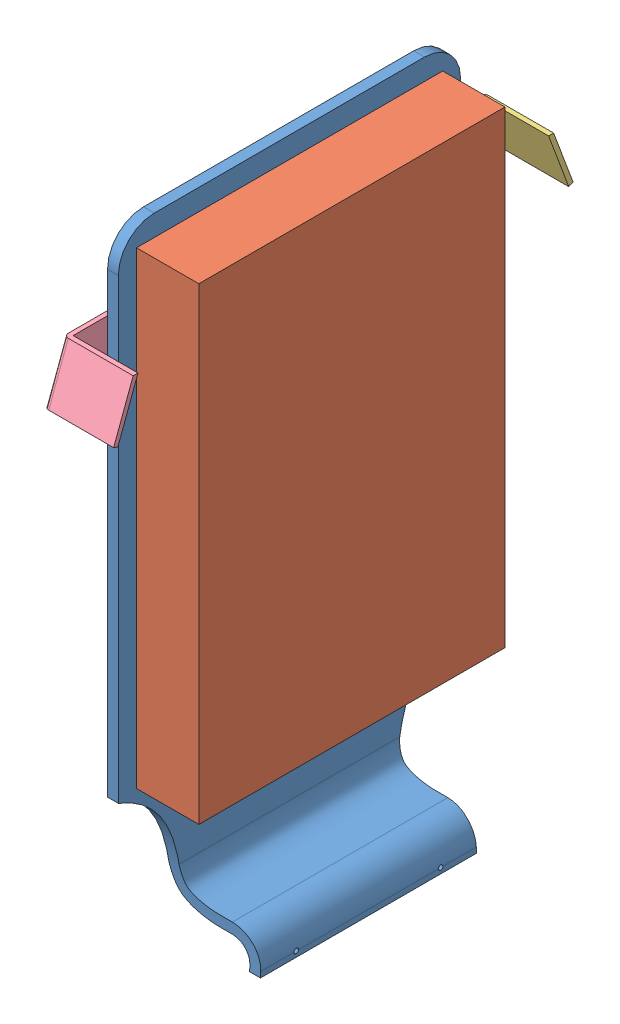
SolidWorks assembly MS-70001-XA-Head Restraint Assembly, configuration Default. Lengths in mm.
Overall size (66.68 448.8 324.07).
4 component instances, 4 part files, 1 mates.
Components (placement in the parent):
- MS-70001-AG-Head_Restraint-1: MS-70001-AG-Head_Restraint [Default] at (207.0378 -6.087 347.9488) size (66.44 448.8 241.3)
- MS-70001-AB-Head Restraint Padding-1: MS-70001-AB-Head Restraint Padding [Default] at (158.9013 216.3377 354.6269) size (43.94 330.2 215.9)
- MS-70001-AC-Right Head Restraint Tab-2: MS-70001-AC-Right Head Restraint Tab [Default] at (147.9793 388.883 235.0151) x (0 0 1) z (-1 0 0) size (49.06 38.1 49.02)
- MS-70001-AC-Left Head Restraint Tab-3: MS-70001-AC-Left Head Restraint Tab [Default] at (151.2813 388.883 461.0827) x (0 0 -1) z (1 0 0) size (48.94 38.1 48.89)
Mates (geometry in assembly coordinates):
- Coincident5: coincident anti-aligned: plane of MS-70001-AG-Head_Restraint-1 through (158.9013 36.3112 468.5988) normal (1 0 0); plane of MS-70001-AB-Head Restraint Padding-1 through (158.9013 216.3377 354.6269) normal (-1 0 0)
